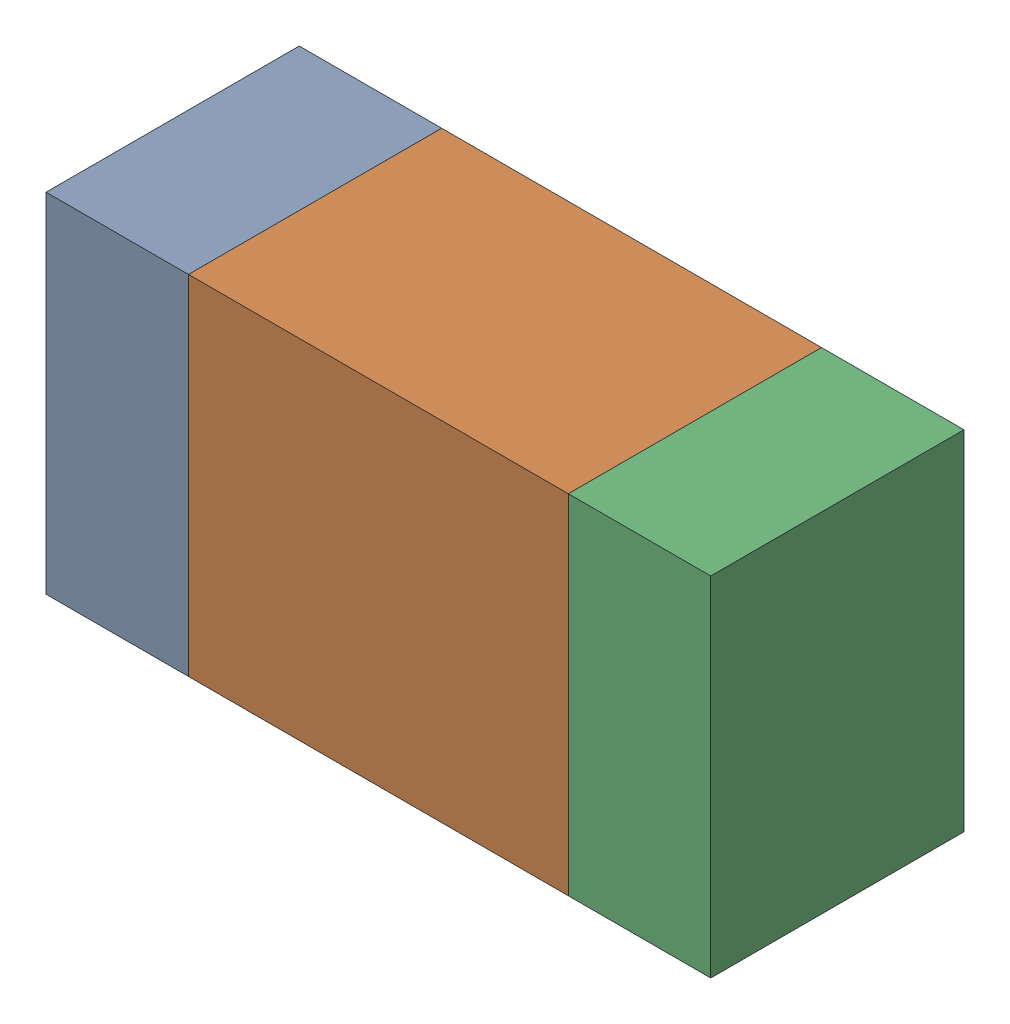
SolidWorks assembly R503_1PCB, configuration Default. Lengths in mm.
Overall size (1.05 0.55 0.4).
6 component instances, 2 part files, 0 mates.
Components (placement in the parent):
- 854785432-1: 854785432 [Default] at (156.2376 117.7501 0) size (0.22 0.55 0.4)
  - Extruded-1: Extruded [Default] at origin size (0.22 0.55 0.4)
- 854785568-1: 854785568 [Default] at (156.6501 117.7501 0) size (0.6 0.55 0.4)
  - Extruded_2-1: Extruded_2 [Default] at origin size (0.6 0.55 0.4)
- 854785432-2: 854785432 [Default] at (157.0626 117.7501 0) size (0.22 0.55 0.4)
  - Extruded-1: Extruded [Default] at origin size (0.22 0.55 0.4)
